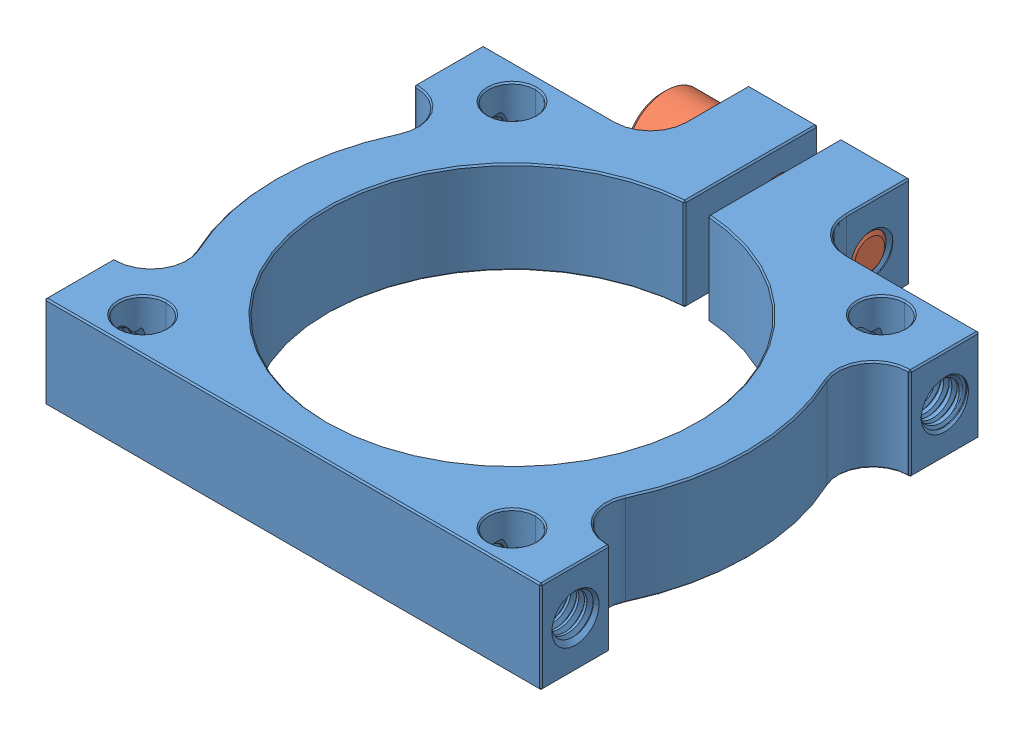
SolidWorks assembly 2-Side, 2-Post Clamping Mount (43mm Width, 32mm Bore)1401-0043-0032, configuration Default. Lengths in mm.
Overall size (43.01 9.67 47.83).
2 component instances, 2 part files, 0 mates.
Components (placement in the parent):
- 1401-0043-0032.STEP-1: 1401-0043-0032.STEP [Default] at (-48.6533 15.5025 19.3874) size (43.01 8 46.5)
- 2800-0004-0014_90128A207.STEP-1: 2800-0004-0014_90128A207.STEP [Default] at (-41.6533 15.5025 -4.6126) x (0 0.538068 -0.842901) z (1 0 0) size (7 7 18.01)
